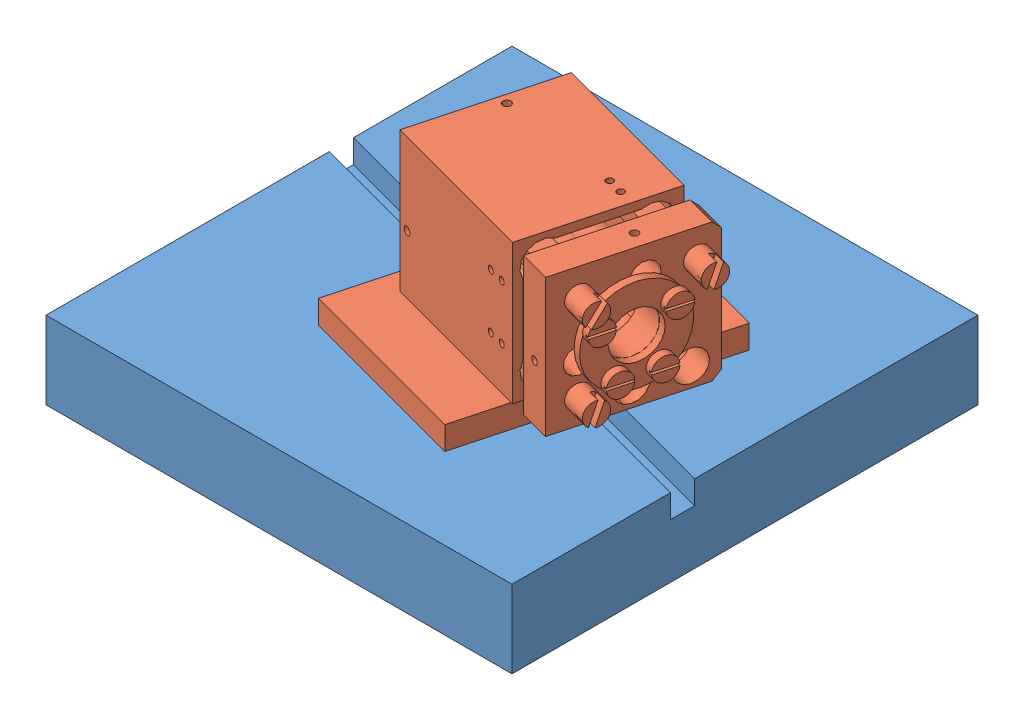
SolidWorks assembly Assem4, configuration Default. Lengths in mm.
Overall size (60 31 60).
2 component instances, 2 part files, 4 mates.
Components (placement in the parent):
- deflectr_holder_slot-1: deflectr_holder_slot [Default] at origin size (60 10 60)
- ASM003_fast_stage-1: ASM003_fast_stage [Default] at (27.3615 24.6882 13.862) x (0.965926 0 0.258819) z (-0.258819 0 0.965926) size (32.45 22.3 32)
Mates (geometry in assembly coordinates):
- Parallel1: parallel: plane of deflectr_holder_slot-1 through (0 10 0) normal (0 1 0); line of ASM003_fast_stage-1 through (8.1978 10.6594 4.9094) axis (-0.965926 0 -0.258819)
- Parallel2: parallel: line of deflectr_holder_slot-1 through (-30 10 -6.4856) axis (0.965926 0 0.258819); line of ASM003_fast_stage-1 through (-4.9978 21.0179 -10.1031) axis (0.965926 0 0.258819)
- Coincident3: coincident: line of deflectr_holder_slot-1 through (-30 10 -6.4856) axis (0.965926 0 0.258819); line of ASM003_fast_stage-1 through (8.4877 10 3.8272) axis (-0.965926 0 -0.258819)
- Coincident4: coincident anti-aligned: plane of deflectr_holder_slot-1 through (0 10 0) normal (0 1 0); plane of ASM003_fast_stage-1 through (-3.0606 10 -17.3327) normal (0 -1 0)
